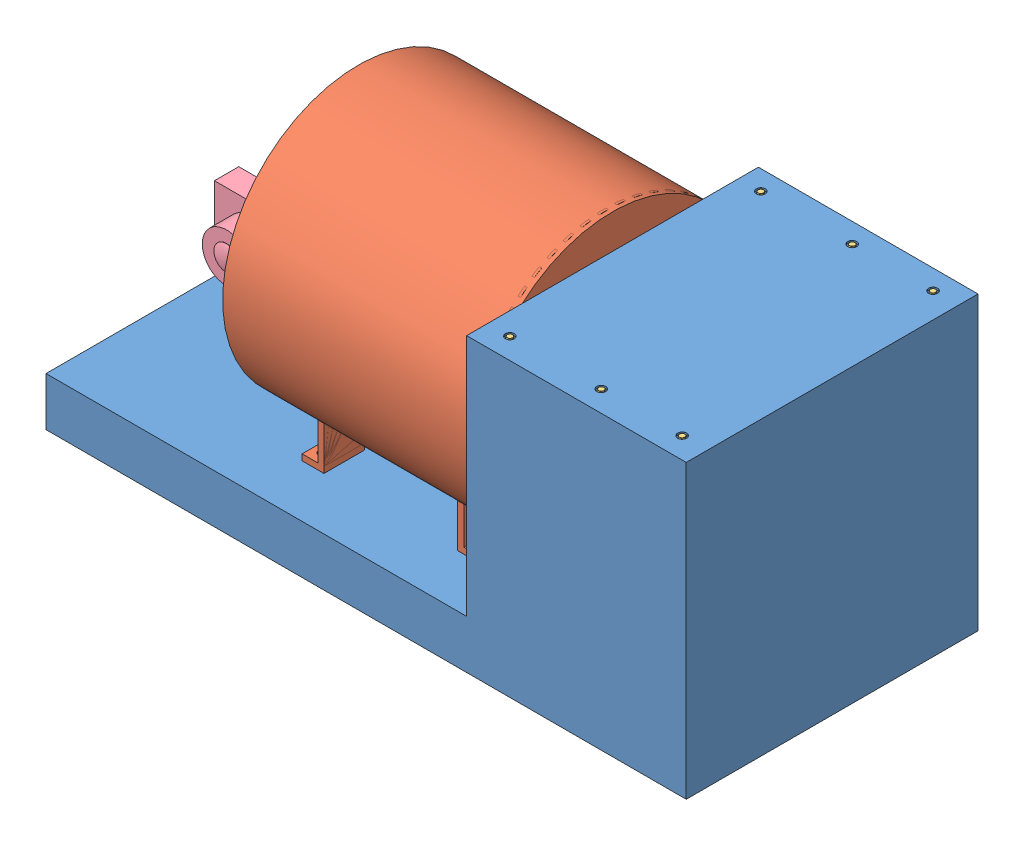
SolidWorks assembly flight recorder, configuration Default. Lengths in mm.
Overall size (668.85 340.7 304.8).
17 component instances, 4 part files, 34 mates.
Components (placement in the parent):
- flight recorder bas-1: flight recorder bas [Default] at (270.3534 -292.8005 -83.0485) size (668.85 304.8 304.8)
- Flight recorder case-1: Flight recorder case [Default] at (33.9952 -93.8773 -83.0485) x (0 0 -1) z (1 0 0) size (283.55 289.9 265.49)
- hex screw gradeab_iso-3: hex screw gradeab_iso [ISO 4017 - M3 x 10-S] at (78.3433 -235.6505 2.7014) x (0 -1 0) z (0 0 1) size (12 6.35 5.5)
- hex screw gradeab_iso-4: hex screw gradeab_iso [ISO 4017 - M3 x 10-S] at (78.3433 -235.6505 -15.9932) x (0 -1 0) z (0 0 1) size (12 6.35 5.5)
- hex screw gradeab_iso-5: hex screw gradeab_iso [ISO 4017 - M3 x 10-S] at (78.3433 -235.6505 -150.1038) x (0 -1 0) z (0.927988 0 -0.372611) size (12 6.35 5.5)
- hex screw gradeab_iso-6: hex screw gradeab_iso [ISO 4017 - M3 x 10-S] at (243.6471 -235.6505 -150.1038) x (0 -1 0) z (-0.843873 0 -0.536543) size (12 6.35 5.5)
- hex screw gradeab_iso-7: hex screw gradeab_iso [ISO 4017 - M3 x 10-S] at (243.6471 -235.6505 2.7014) x (0 -1 0) z (-0.96675 0 0.255722) size (12 6.35 5.5)
- hex screw gradeab_iso-8: hex screw gradeab_iso [ISO 4017 - M3 x 10-S] at (78.3433 -235.6505 -168.7984) x (0 -1 0) z (0.654002 0 -0.756493) size (12 6.35 5.5)
- hex screw gradeab_iso-9: hex screw gradeab_iso [ISO 4017 - M3 x 10-S] at (243.6471 -235.6505 -168.7984) x (0 -1 0) z (-0.909454 0 -0.415805) size (12 6.35 5.5)
- hex screw gradeab_iso-10: hex screw gradeab_iso [ISO 4017 - M3 x 10-S] at (243.6471 -235.6505 -15.9932) x (0 -1 0) z (-0.074143 0 -0.997248) size (12 6.35 5.5)
- flight recorder underwater sensor-2: flight recorder underwater sensor [Default] at (-6.6448 -93.8773 -83.0485) size (76.2 76.2 208.47)
- hex screw gradeab_iso-11: hex screw gradeab_iso [ISO 4017 - M3 x 30-N] at (318.0728 11.9995 -214.8654) x (0 -1 0) z (0 0 1) size (32 6.35 5.5)
- hex screw gradeab_iso-12: hex screw gradeab_iso [ISO 4017 - M3 x 30-N] at (413.5391 11.9995 -214.8654) x (0 -1 0) z (0 0 1) size (32 6.35 5.5)
- hex screw gradeab_iso-13: hex screw gradeab_iso [ISO 4017 - M3 x 30-N] at (497.9901 11.9995 -214.8654) x (0 -1 0) z (0 0 1) size (32 6.35 5.5)
- hex screw gradeab_iso-14: hex screw gradeab_iso [ISO 4017 - M3 x 30-N] at (497.9901 11.9995 47.2997) x (0 -1 0) z (0 0 1) size (32 6.35 5.5)
- hex screw gradeab_iso-15: hex screw gradeab_iso [ISO 4017 - M3 x 30-N] at (413.5391 11.9995 47.2997) x (0 -1 0) z (0 0 1) size (32 6.35 5.5)
- hex screw gradeab_iso-16: hex screw gradeab_iso [ISO 4017 - M3 x 30-N] at (318.0728 11.9995 47.2997) x (0 -1 0) z (0 0 1) size (32 6.35 5.5)
Mates (geometry in assembly coordinates):
- Coincident5: coincident anti-aligned: plane of flight recorder bas-1 through (270.3534 -242.0005 -83.0485) normal (0 1 0); plane of Flight recorder case-1 through (287.9952 -242.0005 -83.0485) normal (0 -1 0)
- Width2: width: plane of flight recorder bas-1 through (16.3534 -242.0005 -235.4485) normal (0 0 -1); plane of flight recorder bas-1 through (16.3534 -242.0005 69.3515) normal (0 0 1); cylinder of Flight recorder case-1 through (33.9952 -93.8773 -83.0485) axis (1 0 0) radius 141.7732
- Coincident6: coincident anti-aligned: plane of flight recorder bas-1 through (294.9302 11.9995 69.3515) normal (-1 0 0); circle of Flight recorder case-1
- Concentric71: concentric aligned: cylinder of Flight recorder case-1 through (78.3433 -235.6505 2.7014) axis (0 1 0) radius 1.8; cylinder of hex screw gradeab_iso-3 through (78.3433 -235.6505 2.7014) axis (0 1 0) radius 1.5
- Coincident91: coincident anti-aligned: plane of Flight recorder case-1 through (78.3433 -237.6505 -1.9741) normal (0 1 0); plane of hex screw gradeab_iso-3 through (81.5188 -237.6505 2.7014) normal (0 -1 0)
- Concentric81: concentric aligned: cylinder of Flight recorder case-1 through (78.3433 -235.6505 -15.9932) axis (0 1 0) radius 1.8; cylinder of hex screw gradeab_iso-4 through (78.3433 -235.6505 -15.9932) axis (0 1 0) radius 1.5
- Coincident101: coincident anti-aligned: plane of Flight recorder case-1 through (78.3433 -237.6505 -20.6687) normal (0 1 0); plane of hex screw gradeab_iso-4 through (81.5188 -237.6505 -15.9932) normal (0 -1 0)
- Screw1: screw = 1 aligned: cylinder of Flight recorder case-1 through (243.6471 -235.6505 2.7014) axis (0 1 0) radius 1.8; cylinder of hex screw gradeab_iso-7 through (243.6471 -235.6505 2.7014) axis (0 1 0) radius 1.5
- Screw2: screw = 1 aligned: cylinder of Flight recorder case-1 through (243.6471 -235.6505 -15.9932) axis (0 1 0) radius 1.8; circle of hex screw gradeab_iso-10
- LimitDistance1: limit distance = 0 mm anti-aligned: plane of hex screw gradeab_iso-7 through (244.4592 -237.6505 5.7713) normal (0 -1 0); plane of Flight recorder case-1 through (243.6471 -237.6505 -1.9741) normal (0 1 0)
- LimitDistance2: limit distance = 0 mm anti-aligned: plane of Flight recorder case-1 through (243.6471 -237.6505 -20.6687) normal (0 1 0); plane of hex screw gradeab_iso-10 through (240.4805 -237.6505 -15.7578) normal (0 -1 0)
- Screw3: screw = 1 aligned: cylinder of Flight recorder case-1 through (78.3433 -235.6505 -168.7984) axis (0 1 0) radius 1.8; circle of hex screw gradeab_iso-8
- LimitDistance3: limit distance = 0 mm anti-aligned: plane of hex screw gradeab_iso-8 through (75.9412 -237.6505 -170.8752) normal (0 -1 0); plane of Flight recorder case-1 through (78.3433 -237.6505 -164.1229) normal (0 1 0)
- Screw4: screw = 1 aligned: cylinder of Flight recorder case-1 through (78.3433 -235.6505 -150.1038) axis (0 1 0) radius 1.8; cylinder of hex screw gradeab_iso-5 through (78.3433 -235.6505 -150.1038) axis (0 1 0) radius 1.5
- LimitDistance4: limit distance = 0 mm anti-aligned: plane of hex screw gradeab_iso-5 through (77.1601 -237.6505 -153.0506) normal (0 -1 0); plane of Flight recorder case-1 through (78.3433 -237.6505 -145.4283) normal (0 1 0)
- Screw5: screw = 1 aligned: cylinder of Flight recorder case-1 through (243.6471 -235.6505 -168.7984) axis (0 1 0) radius 1.8; cylinder of hex screw gradeab_iso-9 through (243.6471 -235.6505 -168.7984) axis (0 1 0) radius 1.5
- LimitDistance6: limit distance = 0 mm anti-aligned: plane of hex screw gradeab_iso-9 through (242.3268 -237.6505 -165.9105) normal (0 -1 0); plane of Flight recorder case-1 through (243.6471 -237.6505 -164.1229) normal (0 1 0)
- Screw6: screw = 1 aligned: cylinder of Flight recorder case-1 through (243.6471 -235.6505 -150.1038) axis (0 1 0) radius 1.8; cylinder of hex screw gradeab_iso-6 through (243.6471 -235.6505 -150.1038) axis (0 1 0) radius 1.5
- LimitDistance7: limit distance = 0 mm anti-aligned: plane of hex screw gradeab_iso-6 through (241.9434 -237.6505 -147.4242) normal (0 -1 0); plane of Flight recorder case-1 through (243.6471 -237.6505 -145.4283) normal (0 1 0)
- Coincident15: coincident anti-aligned: plane of Flight recorder case-1 through (31.4552 -93.8773 -83.0485) normal (-1 0 0); plane of flight recorder underwater sensor-2 through (31.4552 -93.8773 -83.0485) normal (1 0 0)
- Width4: width: plane of flight recorder underwater sensor-2 through (-44.7448 -55.7773 -159.2485) normal (0 0 -1); plane of flight recorder underwater sensor-2 through (-44.7448 -55.7773 -6.8485) normal (0 0 1); cylinder of Flight recorder case-1 through (33.9952 -93.8773 -83.0485) axis (1 0 0) radius 141.7732
- Width5: width: plane of flight recorder underwater sensor-2 through (-44.7448 -131.9773 -133.8485) normal (0 -1 0); plane of flight recorder underwater sensor-2 through (-44.7448 -55.7773 -159.2485) normal (0 1 0); cylinder of Flight recorder case-1 through (33.9952 -93.8773 -83.0485) axis (1 0 0) radius 141.7732
- Concentric91: concentric aligned: cylinder of flight recorder bas-1 through (318.0728 11.9995 -214.8654) axis (0 1 0) radius 1.8; cylinder of hex screw gradeab_iso-11 through (318.0728 11.9995 -214.8654) axis (0 1 0) radius 1.5
- Coincident161: coincident anti-aligned: plane of flight recorder bas-1 through (322.7483 9.9995 -214.8654) normal (0 1 0); plane of hex screw gradeab_iso-11 through (321.2482 9.9995 -214.8654) normal (0 -1 0)
- Concentric101: concentric aligned: cylinder of flight recorder bas-1 through (413.5391 11.9995 -214.8654) axis (0 1 0) radius 1.8; cylinder of hex screw gradeab_iso-12 through (413.5391 11.9995 -214.8654) axis (0 1 0) radius 1.5
- Coincident171: coincident anti-aligned: plane of flight recorder bas-1 through (418.2146 9.9995 -214.8654) normal (0 1 0); plane of hex screw gradeab_iso-12 through (416.7145 9.9995 -214.8654) normal (0 -1 0)
- Concentric111: concentric aligned: cylinder of flight recorder bas-1 through (497.9901 11.9995 -214.8654) axis (0 1 0) radius 1.8; cylinder of hex screw gradeab_iso-13 through (497.9901 11.9995 -214.8654) axis (0 1 0) radius 1.5
- Coincident181: coincident anti-aligned: plane of flight recorder bas-1 through (502.6656 9.9995 -214.8654) normal (0 1 0); plane of hex screw gradeab_iso-13 through (501.1655 9.9995 -214.8654) normal (0 -1 0)
- Concentric121: concentric aligned: cylinder of flight recorder bas-1 through (497.9901 11.9995 47.2997) axis (0 1 0) radius 1.8; cylinder of hex screw gradeab_iso-14 through (497.9901 11.9995 47.2997) axis (0 1 0) radius 1.5
- Coincident191: coincident anti-aligned: plane of flight recorder bas-1 through (502.6656 9.9995 47.2997) normal (0 1 0); plane of hex screw gradeab_iso-14 through (501.1655 9.9995 47.2997) normal (0 -1 0)
- Concentric131: concentric aligned: cylinder of flight recorder bas-1 through (413.5391 11.9995 47.2997) axis (0 1 0) radius 1.8; cylinder of hex screw gradeab_iso-15 through (413.5391 11.9995 47.2997) axis (0 1 0) radius 1.5
- Coincident201: coincident anti-aligned: plane of flight recorder bas-1 through (418.2146 9.9995 47.2997) normal (0 1 0); plane of hex screw gradeab_iso-15 through (416.7145 9.9995 47.2997) normal (0 -1 0)
- Concentric141: concentric aligned: cylinder of flight recorder bas-1 through (318.0728 11.9995 47.2997) axis (0 1 0) radius 1.8; cylinder of hex screw gradeab_iso-16 through (318.0728 11.9995 47.2997) axis (0 1 0) radius 1.5
- Coincident211: coincident anti-aligned: plane of flight recorder bas-1 through (322.7483 9.9995 47.2997) normal (0 1 0); plane of hex screw gradeab_iso-16 through (321.2482 9.9995 47.2997) normal (0 -1 0)
